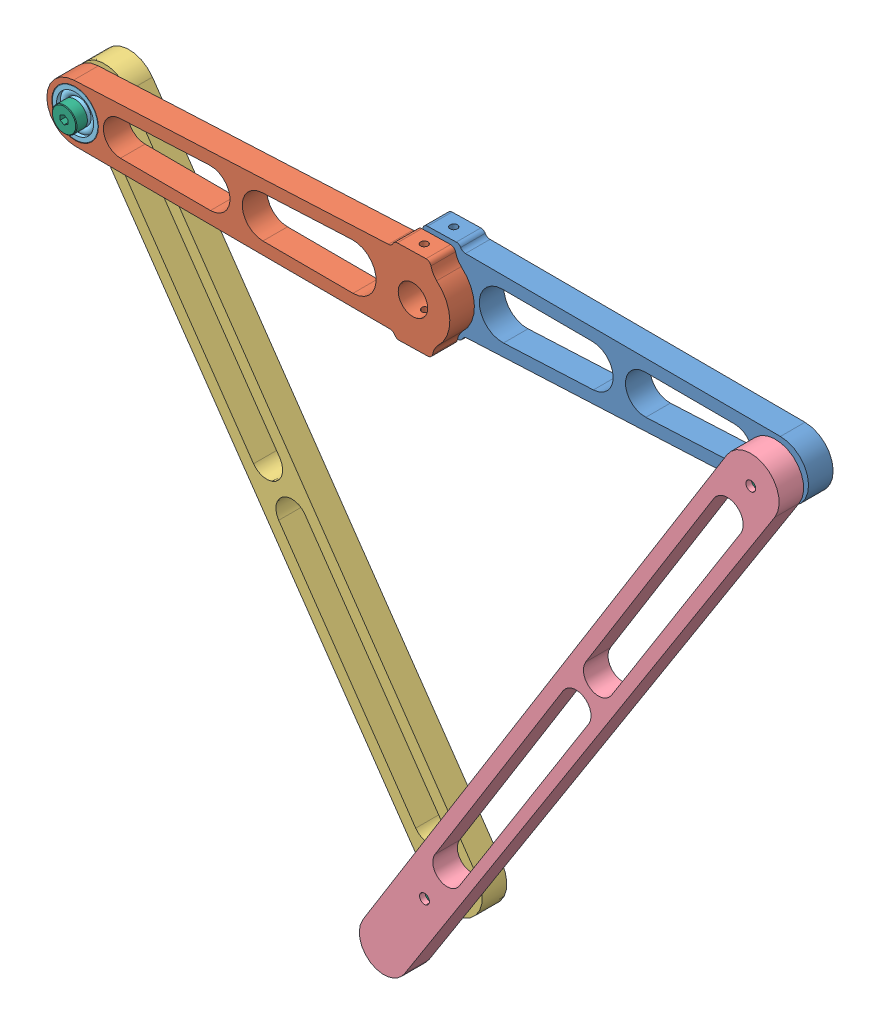
SolidWorks assembly Leg Assembly, configuration Default. Lengths in mm.
Overall size (306.78 269.08 31).
13 component instances, 7 part files, 26 mates.
Components (placement in the parent):
- Outer Short Link-1: Outer Short Link [Default] at (74.6286 151.6715 599.2565) x (-0.022471 0.999747 0) z (0.999747 0.022471 0) size (34 10 164)
- Inner Short Link-1: Inner Short Link [Default] at (74.6286 151.6715 611.2565) x (0.022471 -0.999747 0) z (-0.999747 -0.022471 0) size (33.99 10 164)
- Long Link-1: Long Link [Default] at (-62.8367 148.5818 609.2565) x (0.568628 -0.822595 0) z (0.822595 0.568628 0) size (273 10 23)
- Extra Long Link-1: Extra Long Link [Default] at (212.0939 154.7613 621.2565) x (-0.531094 -0.847313 0) z (0.847313 -0.531094 0) size (301.49 10 23)
- SKF - 626 - 8,SI,NC,8_68-8: SKF - 626 - 8,SI,NC,8_68 [SKF - 626 - 8,SI,NC,8_68] at (212.0939 154.7613 602.2565) x (0 0 -1) z (0.999791 0.020442 0) size (6 19 19)
- ISO 7379 - 6 x 10 --- C-7: ISO 7379 - 6 x 10 --- C [ISO 7379 - 6 x 10 --- C] at (212.0939 154.7613 594.7565) x (0 0 1) z (0.999947 -0.010306 0) size (24.25 10 10)
- Leg Spacer-1: Leg Spacer [Default] at (212.0939 154.7613 611.2565) x (-0.080045 0.996791 0) z (-0.996791 -0.080045 0) size (8.2 6 8.2)
- SKF - 626 - 8,SI,NC,8_68-9: SKF - 626 - 8,SI,NC,8_68 [SKF - 626 - 8,SI,NC,8_68] at (-62.8367 148.5818 618.2565) x (0 0 1) z (-1 0 0) size (6 19 19)
- SKF - 626 - 8,SI,NC,8_68-10: SKF - 626 - 8,SI,NC,8_68 [SKF - 626 - 8,SI,NC,8_68] at (79.3203 -57.0669 602.2565) x (0 0 -1) z (1 0 0) size (6 19 19)
- ISO 7379 - 6 x 10 --- C-8: ISO 7379 - 6 x 10 --- C [ISO 7379 - 6 x 10 --- C] at (79.3203 -57.0669 594.7565) x (0 0 1) z (-1 0 0) size (24.25 10 10)
- Leg Spacer-2: Leg Spacer [Default] at (79.3203 -57.0669 605.2565) x (0.117154 0.993114 0) z (0.993114 -0.117154 0) size (8.2 6 8.2)
- ISO 7379 - 6 x 10 --- C-9: ISO 7379 - 6 x 10 --- C [ISO 7379 - 6 x 10 --- C] at (-62.8367 148.5818 625.7565) x (0 0 -1) z (1 0 0) size (24.25 10 10)
- Leg Spacer-3: Leg Spacer [Default] at (-62.8367 148.5818 609.2565) x (0.995138 0.09849 0) z (0.09849 -0.995138 0) size (8.2 6 8.2)
Mates (geometry in assembly coordinates):
- Concentric3: concentric: cylinder of Outer Short Link-1 through (74.6286 151.6715 609.2565) axis (0 0 -1) radius 10; cylinder of Inner Short Link-1 through (74.6286 151.6715 621.2565) axis (0 0 -1) radius 6
- Concentric8: concentric: cylinder of Inner Short Link-1 through (-62.8367 148.5818 621.2565) axis (0 0 -1) radius 5; cylinder of Long Link-1 through (-62.8367 148.5818 599.2565) axis (0 0 1) radius 2
- Concentric9: concentric: cylinder of Extra Long Link-1 through (212.0939 154.7613 611.2565) axis (0 0 1) radius 2; cylinder of Outer Short Link-1 through (212.0939 154.7613 609.2565) axis (0 0 -1) radius 5
- Concentric11: concentric: cylinder of Long Link-1 through (79.3203 -57.0669 599.2565) axis (0 0 1) radius 5; cylinder of Extra Long Link-1 through (79.3203 -57.0669 611.2565) axis (0 0 1) radius 2
- Concentric12: concentric: cylinder of Outer Short Link-1 through (212.0939 154.7613 605.2565) axis (0 0 -1) radius 9.5; cylinder of SKF - 626 - 8,SI,NC,8_68-8 through (212.0939 154.7613 622.894) axis (0 0 -1) radius 3
- Coincident8: coincident: plane of Outer Short Link-1 through (212.0939 154.7613 605.2565) normal (0 0 -1); plane of SKF - 626 - 8,SI,NC,8_68-8 through (211.9395 162.3097 605.2565) normal (0 0 1)
- Concentric13: concentric: cylinder of SKF - 626 - 8,SI,NC,8_68-8 through (212.0939 154.7613 622.894) axis (0 0 -1) radius 4.95; cylinder of ISO 7379 - 6 x 10 --- C-7 through (212.0939 154.7613 588.4065) axis (0 0 -1) radius 2.995
- Coincident10: coincident: plane of SKF - 626 - 8,SI,NC,8_68-8 through (212.0264 158.0606 599.2565) normal (0 0 -1); plane of ISO 7379 - 6 x 10 --- C-7 through (212.0423 149.7615 599.2565) normal (0 0 1)
- Concentric14: concentric: cylinder of ISO 7379 - 6 x 10 --- C-7 through (212.0939 154.7613 588.4065) axis (0 0 -1) radius 2.995; cylinder of Leg Spacer-1 through (212.0939 154.7613 605.2565) axis (0 0 1) radius 3.1
- Coincident11: coincident: plane of SKF - 626 - 8,SI,NC,8_68-8 through (211.9927 159.7102 605.2565) normal (0 0 1); plane of Leg Spacer-1 through (212.0939 154.7613 605.2565) normal (0 0 -1)
- Coincident12: coincident: plane of Extra Long Link-1 through (212.0939 154.7613 611.2565) normal (0 0 -1); plane of Leg Spacer-1 through (212.0939 154.7613 611.2565) normal (0 0 1)
- Coincident14: coincident: plane of Outer Short Link-1 through (59.4978 134.3271 599.2565) normal (0 0 -1); plane of Long Link-1 through (-62.8367 148.5818 599.2565) normal (0 0 -1)
- Concentric22: concentric: cylinder of Inner Short Link-1 through (-62.8367 148.5818 615.2565) axis (0 0 1) radius 9.5; cylinder of SKF - 626 - 8,SI,NC,8_68-9 through (-62.8367 148.5818 597.619) axis (0 0 1) radius 3
- Concentric231: concentric: cylinder of Long Link-1 through (79.3203 -57.0669 605.2565) axis (0 0 -1) radius 9.5; cylinder of SKF - 626 - 8,SI,NC,8_68-10 through (79.3203 -57.0669 622.894) axis (0 0 -1) radius 3
- Coincident15: coincident: plane of Long Link-1 through (79.3203 -57.0669 605.2565) normal (0 0 -1); plane of SKF - 626 - 8,SI,NC,8_68-10 through (79.3203 -49.5169 605.2565) normal (0 0 1)
- Concentric24: concentric: cylinder of SKF - 626 - 8,SI,NC,8_68-10 through (79.3203 -57.0669 622.894) axis (0 0 -1) radius 3; cylinder of ISO 7379 - 6 x 10 --- C-8 through (79.3203 -57.0669 588.4065) axis (0 0 -1) radius 2.995
- Coincident16: coincident: plane of SKF - 626 - 8,SI,NC,8_68-10 through (79.3203 -53.7669 599.2565) normal (0 0 -1); plane of ISO 7379 - 6 x 10 --- C-8 through (79.3203 -52.0669 599.2565) normal (0 0 1)
- Concentric25: concentric: cylinder of ISO 7379 - 6 x 10 --- C-8 through (79.3203 -57.0669 588.4065) axis (0 0 -1) radius 2.995; cylinder of Leg Spacer-2 through (79.3203 -57.0669 611.2565) axis (0 0 -1) radius 3.1
- Coincident17: coincident: plane of SKF - 626 - 8,SI,NC,8_68-10 through (79.3203 -52.1169 605.2565) normal (0 0 1); plane of Leg Spacer-2 through (79.3203 -57.0669 605.2565) normal (0 0 -1)
- Concentric26: concentric: cylinder of SKF - 626 - 8,SI,NC,8_68-9 through (-62.8367 148.5818 597.619) axis (0 0 1) radius 3; cylinder of ISO 7379 - 6 x 10 --- C-9 through (-62.8367 148.5818 632.1065) axis (0 0 1) radius 2.995
- Coincident18: coincident: plane of SKF - 626 - 8,SI,NC,8_68-9 through (-62.8367 151.8818 621.2565) normal (0 0 1); plane of ISO 7379 - 6 x 10 --- C-9 through (-62.8367 153.5818 621.2565) normal (0 0 -1)
- Concentric27: concentric: cylinder of ISO 7379 - 6 x 10 --- C-9 through (-62.8367 148.5818 632.1065) axis (0 0 1) radius 2.995; cylinder of Leg Spacer-3 through (-62.8367 148.5818 615.2565) axis (0 0 -1) radius 3.1
- Coincident19: coincident: plane of SKF - 626 - 8,SI,NC,8_68-9 through (-62.8367 153.5318 615.2565) normal (0 0 -1); plane of Leg Spacer-3 through (-62.8367 148.5818 615.2565) normal (0 0 1)
- Coincident20: coincident: plane of Inner Short Link-1 through (-62.8367 148.5818 615.2565) normal (0 0 1); plane of SKF - 626 - 8,SI,NC,8_68-9 through (-62.8367 156.1318 615.2565) normal (0 0 -1)
- Coincident21: coincident: plane of Long Link-1 through (-62.8367 148.5818 609.2565) normal (0 0 1); plane of Leg Spacer-3 through (-62.8367 148.5818 609.2565) normal (0 0 -1)
- Parallel1: parallel: plane of Outer Short Link-1 through (66.7485 168.4987 609.2565) normal (-0.022471 0.999747 0); plane of Inner Short Link-1 through (81.7448 168.8309 621.2565) normal (-0.022471 0.999747 0)
